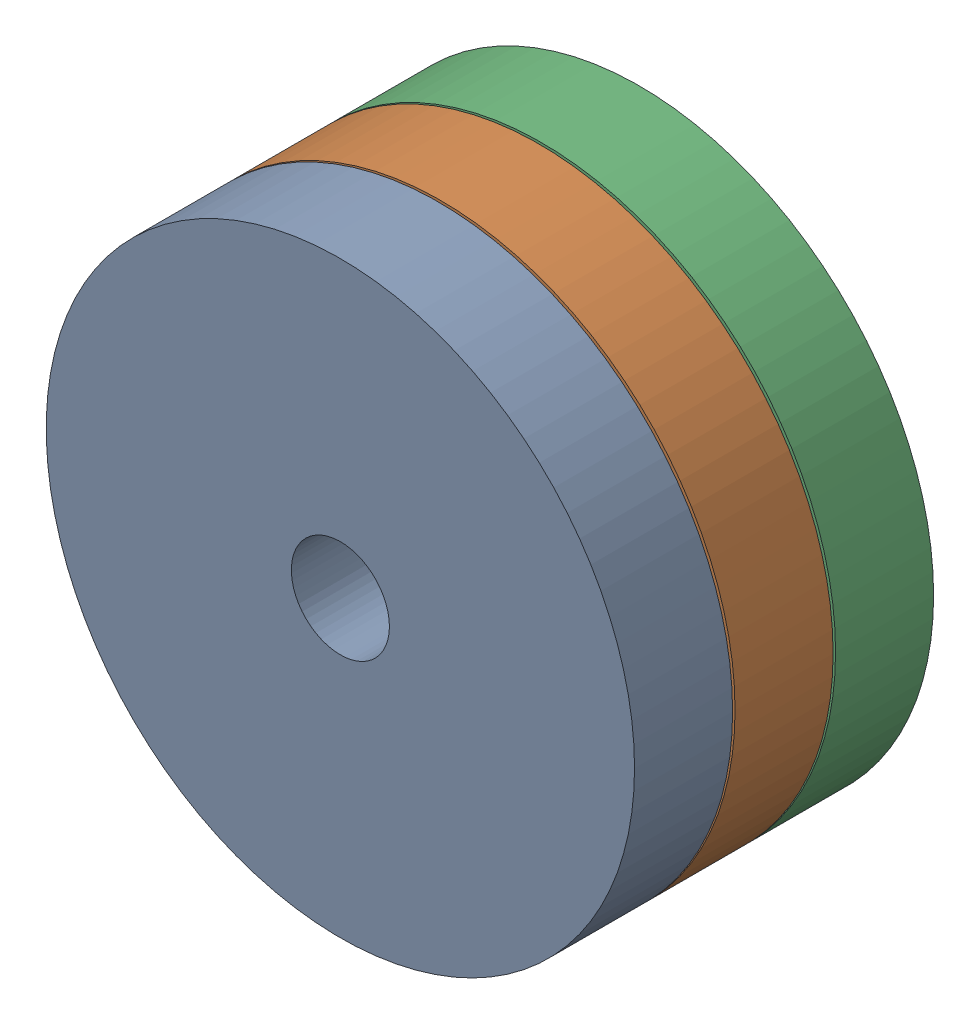
SolidWorks assembly Produit2, configuration Default. Lengths in mm.
Overall size (120 120 61).
3 component instances, 1 part files, 0 mates.
Components (placement in the parent):
- Part_Gateau-1: Part_Gateau [Default] at (0 0 41) size (120 120 20)
- Part_Gateau-2: Part_Gateau [Default] at (0 0 20.5) size (120 120 20)
- Part_Gateau-3: Part_Gateau [Default] at origin size (120 120 20)
